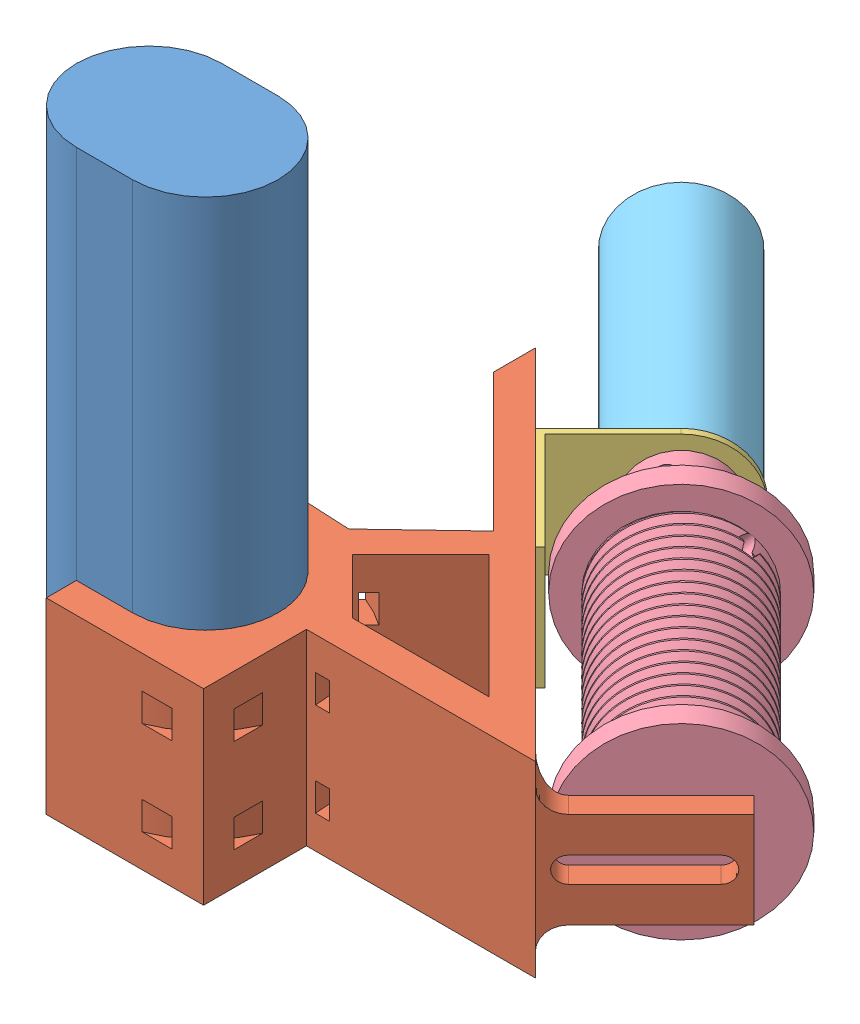
SolidWorks assembly assembly, configuration Default. Lengths in mm.
Overall size (312.03 128.28 273.22).
5 component instances, 5 part files, 10 mates.
Components (placement in the parent):
- post-1: post [Default] at (25.0134 6.7287 96.5918) size (43 120 31)
- Smaller SecondSupport-1: Smaller SecondSupport [Default] at (25.0134 26.7287 96.5918) size (298.83 40 253.53)
- braket-1: braket [Default] at (49.8129 26.7287 39.0237) x (0.707107 0 0.707107) z (0 1 0) size (31 35 26)
- threaded_cable_retractor-1: threaded_cable_retractor [Default] at (55.4697 26.7287 13.5679) x (0.495444 -0.713492 -0.495444) z (-0.504515 -0.700664 0.504515) size (40 148 40)
- DC MOTOR-1: DC MOTOR [Default] at (8.4471 26.7287 -33.4547) x (0.605351 -0.516817 -0.605351) z (-0.365445 -0.856096 0.365445) size (25 76 25)
Mates (geometry in assembly coordinates):
- Concentric1: concentric anti-aligned: cylinder of post-1 through (37.0134 126.7287 96.5918) axis (0 -1 0) radius 15.5; cylinder of SecondSupport-1 through (37.0134 6.7287 96.5918) axis (0 1 0) radius 15.5
- Coincident1: coincident aligned: plane of post-1 through (37.0134 6.7287 96.5918) normal (0 -1 0); plane of SecondSupport-1 through (25.0134 6.7287 96.5918) normal (0 -1 0)
- Coincident2: coincident anti-aligned: plane of SecondSupport-1 through (107.381 6.7287 96.5918) normal (0.707107 0 -0.707107); plane of braket-1 through (49.8129 26.7287 39.0237) normal (-0.707107 0 0.707107)
- Parallel1: parallel aligned: plane of SecondSupport-1 through (25.0134 46.7287 96.5918) normal (0 1 0); plane of braket-1 through (39.9134 39.7287 27.0029) normal (0 1 0)
- Coincident4: coincident anti-aligned: line of SecondSupport-1 through (31.0134 26.7287 20.2243) axis (0.707107 0 0.707107); line of braket-1 through (60.773 26.7287 49.9839) axis (-0.707107 0 -0.707107)
- Concentric4: concentric aligned: cylinder of braket-1 through (78.0971 26.7287 36.1953) axis (-0.707107 0 -0.707107) radius 4; cylinder of threaded_cable_retractor-1 through (156.586 26.7287 114.6841) axis (-0.707107 0 -0.707107) radius 15
- Coincident5: coincident anti-aligned: plane of braket-1 through (64.6621 13.7287 4.3755) normal (0.707107 0 0.707107); plane of threaded_cable_retractor-1 through (55.4697 26.7287 13.5679) normal (-0.707107 0 -0.707107)
- Parallel4: parallel aligned: plane of post-1 through (25.0134 126.7287 112.0918) normal (0 0 1); plane of SecondSupport-1 through (58.5764 101.9674 118.5283) normal (0 0 1)
- Coincident6: coincident anti-aligned: plane of braket-1 through (39.9134 13.7287 27.0029) normal (-0.707107 0 -0.707107); plane of DC MOTOR-1 through (54.4091 26.7287 12.5072) normal (0.707107 0 0.707107)
- Concentric5: concentric aligned: cylinder of braket-1 through (78.0971 26.7287 36.1953) axis (-0.707107 0 -0.707107) radius 4; cylinder of DC MOTOR-1 through (62.1872 26.7287 20.2854) axis (-0.707107 0 -0.707107) radius 2
